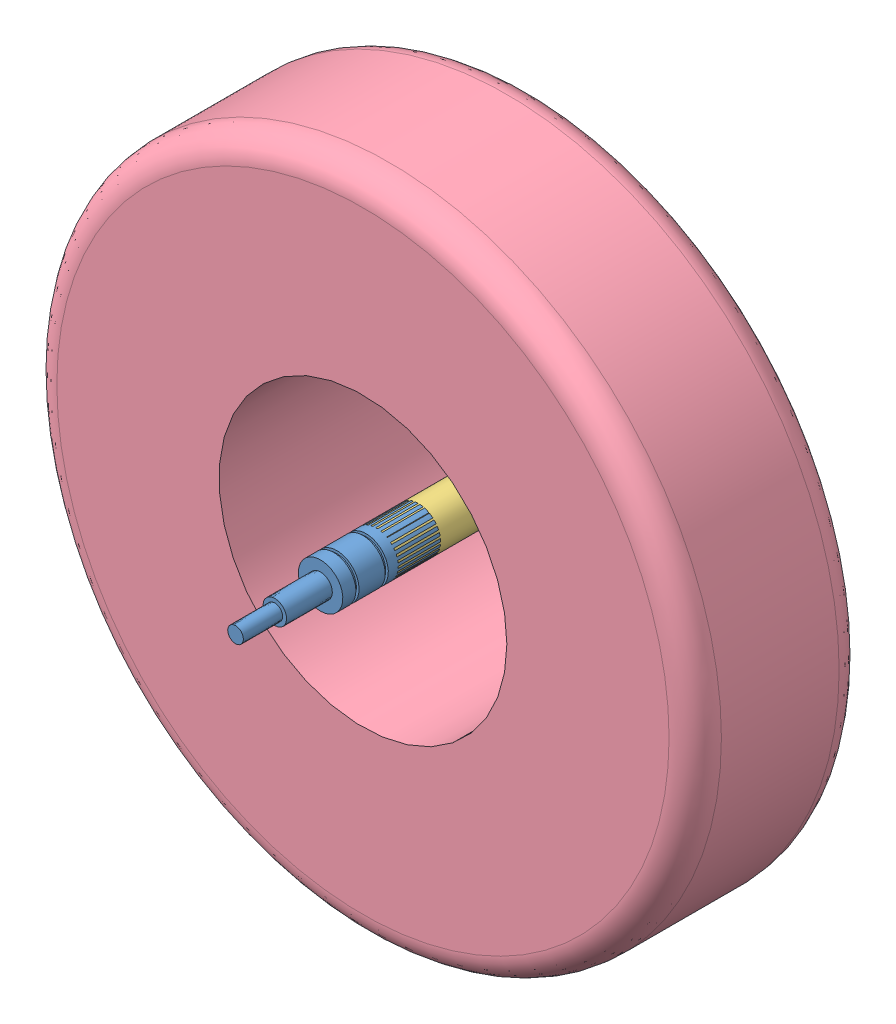
SolidWorks assembly Tire_Assembly, configuration Default. Lengths in mm.
Overall size (254 254 148.7).
7 component instances, 7 part files, 15 mates.
Components (placement in the parent):
- Motor Shaft-1: Motor Shaft [Default] at (-139.6427 50.1612 347.3066) x (0 0 1) z (-0.999276 0.038043 0) size (69.9 17 17)
- Tire_Inboard_Bearing-1: Tire_Inboard_Bearing [Default] at (-139.6427 50.1612 347.1066) x (-0.226181 -0.974085 0) z (0 0 1) size (35 35 10) (hidden)
- Tire_Inner_Cover-1: Tire_Inner_Cover [Default] at (-139.6427 50.1612 347.1066) size (110 110 13) (hidden)
- Tire_Outboard_Splines-1: Tire_Outboard_Splines [Default] at (-139.6427 50.1612 267.1066) x (0.750732 -0.660607 0) z (0 0 1) size (55 55 12)
- Tire_Splined_Shaft-1: Tire_Splined_Shaft [Default] at (-124.6113 23.2956 245.1066) x (0.750732 -0.660607 0) z (0 0 1) size (55 55 97)
- Tire_Updated-1: Tire_Updated [Default] at (-139.6427 50.1612 282.1066) size (254 254 100)
- Flange Coupler-1: Flange Coupler [Default] at (-139.6427 50.1612 378.007) x (0 0 1) z (-0.901253 0.433293 0) size (17.5 45 45) (hidden)
Mates (geometry in assembly coordinates):
- Concentric1: concentric: cylinder of Tire_Outboard_Splines-1 through (-139.6427 50.1612 279.1066) axis (0 0 -1) radius 27.5; cylinder of Tire_Updated-1 through (-139.6427 50.1612 276.6066) axis (0 0 -1) radius 22.5
- Distance1: distance = 2.5 mm: plane of Tire_Outboard_Splines-1 through (-139.6427 50.1612 279.1066) normal (0 0 1); plane of Tire_Updated-1 through (-139.6427 50.1612 276.6066) normal (0 0 1)
- Concentric2: concentric: cylinder of Tire_Splined_Shaft-1 through (-139.6427 50.1612 342.1066) axis (0 0 -1) radius 8.5; cylinder of Tire_Updated-1 through (-139.6427 50.1612 276.6066) axis (0 0 -1) radius 22.5
- Coincident1: coincident: plane of Tire_Outboard_Splines-1 through (-139.6427 50.1612 279.1066) normal (0 0 1); plane of Tire_Splined_Shaft-1 through (-139.6427 50.1612 279.1066) normal (0 0 1)
- Concentric3: concentric: cylinder of Motor Shaft-1 through (-139.6427 50.1612 298.7965) axis (0 0 -1) radius 8.5; cylinder of Tire_Updated-1 through (-139.6427 50.1612 276.6066) axis (0 0 -1) radius 22.5
- Coincident2: coincident: plane of Tire_Outboard_Splines-1 through (-134.1062 62.4736 279.1066) normal (0.750732 -0.660607 0); plane of Tire_Splined_Shaft-1 through (-149.3925 45.1018 282.1066) normal (-0.750732 0.660607 0)
- Coincident3: coincident: plane of Tire_Inner_Cover-1 through (-139.6427 50.1612 347.1066) normal (0 0 -1); plane of Tire_Updated-1 through (-139.6427 50.1612 347.1066) normal (0 0 1)
- Concentric4: concentric: cylinder of Motor Shaft-1 through (-139.6427 50.1612 298.7965) axis (0 0 -1) radius 8.5; cylinder of Tire_Inner_Cover-1 through (-139.6427 50.1612 360.1066) axis (0 0 -1) radius 55
- Concentric5: concentric: cylinder of Motor Shaft-1 through (-139.6427 50.1612 298.7965) axis (0 0 -1) radius 8.5; cylinder of Tire_Inboard_Bearing-1 through (-139.6427 50.1612 357.1066) axis (0 0 -1) radius 17.5
- Distance2: distance = 95 mm: plane of Tire_Inboard_Bearing-1 through (-139.6427 50.1612 357.1066) normal (0 0 1); plane of Tire_Updated-1 through (-139.6427 50.1612 262.1066) normal (0 0 1)
- Coincident4: coincident: plane of Motor Shaft-1 through (-139.3574 57.6557 357.1066) normal (0 0 1); plane of Tire_Inboard_Bearing-1 through (-139.6427 50.1612 357.1066) normal (0 0 1)
- Concentric6: concentric: cylinder of Motor Shaft-1 through (-139.6427 50.1612 298.7965) axis (0 0 -1) radius 4.5; cylinder of Flange Coupler-1 through (-139.6427 50.1612 366.3941) axis (0 0 -1) radius 12
- Coincident6: coincident: plane of Motor Shaft-1 through (-136.1658 53.0179 363.3066) normal (0 0 1); plane of Flange Coupler-1 through (-135.1639 49.7251 363.3066) normal (0 0 -1)
- Concentric8: concentric: circle of assembly; circle of assembly; circle of Motor Shaft-1; circle of Flange Coupler-1
- Coincident8: coincident: circle of assembly; circle of assembly; circle of Motor Shaft-1; circle of Flange Coupler-1
